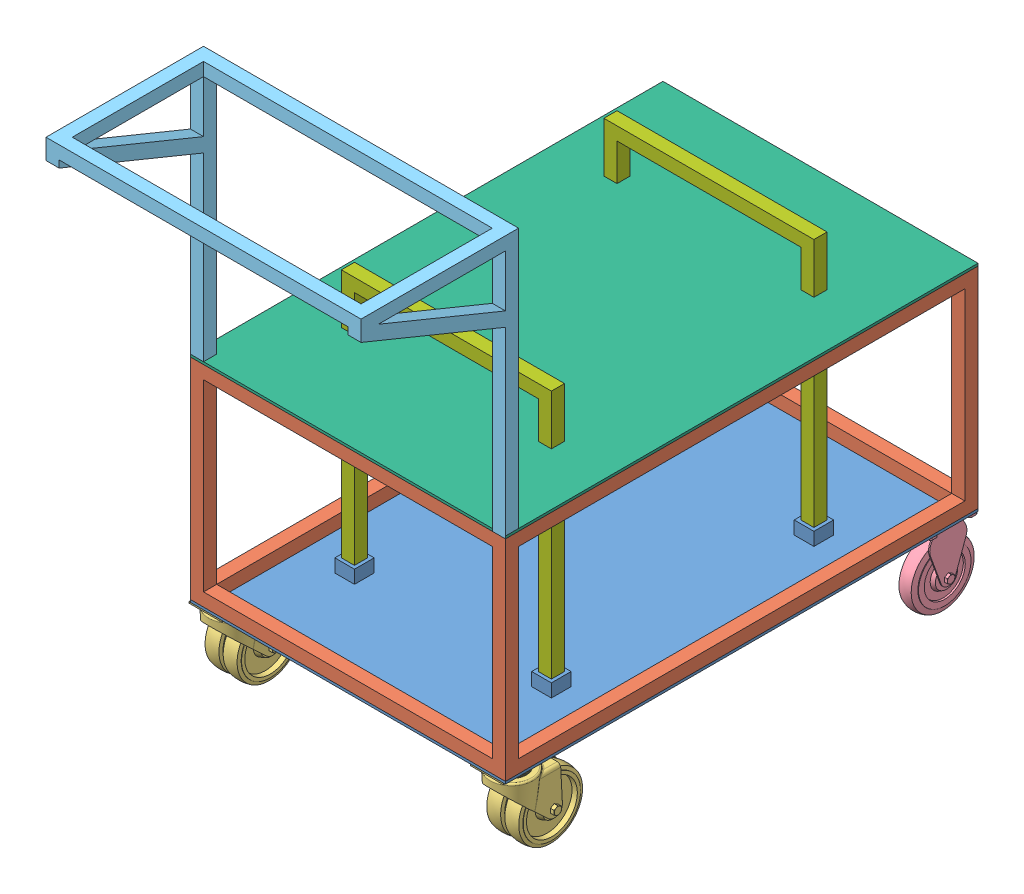
SolidWorks assembly Assem4, configuration Default. Lengths in mm.
Overall size (635.12 1076.33 1211.26).
10 component instances, 7 part files, 28 mates.
Components (placement in the parent):
- bottom plate-1: bottom plate [Default] at (-709.1986 562.6212 534.5092) size (609.6 30.16 914.4)
- frame-1: frame [Default] at (-99.5986 580.0837 534.5092) size (609.6 406.4 914.4)
- 9908T218_Cart-King Caster-1: 9908T218_Cart-King Caster [9908T218] at (-135.1319 562.6212 486.8842) x (0 0 1) z (-1 0 0) size (155.58 149.22 90.11)
- 9908T218_Cart-King Caster-2: 9908T218_Cart-King Caster [9908T218] at (-680.1501 562.6212 486.8842) x (0 0 1) z (-1 0 0) size (155.58 149.22 90.11)
- 2702T53_Cart-King Caster-1: 2702T53_Cart-King Caster [2702T53] at (-133.7299 562.6212 -333.8533) x (0 0 -1) z (1 0 0) size (127 157.16 68.26)
- 2702T53_Cart-King Caster-3: 2702T53_Cart-King Caster [2702T53] at (-675.0674 562.6212 -333.8533) x (0 0 -1) z (1 0 0) size (127 157.16 68.26)
- handle frame-1: handle frame [Default] at (-99.5986 1227.7837 509.1092) x (-1 0 0) z (0 0 -1) size (609.6 508 304.8)
- top plate-1: top plate [Default] at (-709.1986 973.7837 534.5092) size (609.6 4.76 914.4)
- legs-1: legs [Default] at (-607.5986 567.3837 -189.3908) size (406.4 508 25.4)
- legs-2: legs [Default] at (-607.5986 567.3837 318.6092) size (406.4 508 25.4)
Mates (geometry in assembly coordinates):
- Coincident5: coincident anti-aligned: plane of bottom plate-1 through (-709.1986 562.6212 534.5092) normal (0 -1 0); plane of 9908T218_Cart-King Caster-1 through (-166.8819 562.6212 439.2592) normal (0 1 0)
- Coincident6: coincident: line of bottom plate-1 through (-709.1986 562.6212 534.5092) axis (1 0 0); plane of 9908T218_Cart-King Caster-1 through (-103.3819 559.8431 534.5092) normal (0 0 1)
- Coincident10: coincident anti-aligned: plane of bottom plate-1 through (-709.1986 562.6212 534.5092) normal (0 -1 0); plane of 2702T53_Cart-King Caster-1 through (-111.0286 562.6212 -287.8158) normal (0 1 0)
- Coincident13: coincident anti-aligned: plane of bottom plate-1 through (-709.1986 562.6212 534.5092) normal (0 -1 0); plane of 2702T53_Cart-King Caster-2 through (-847.3098 567.3837 -256.8617) normal (0 1 0)
- Coincident17: coincident anti-aligned: plane of bottom plate-1 through (-709.1986 562.6212 534.5092) normal (0 -1 0); plane of 2702T53_Cart-King Caster-3 through (-652.3661 562.6212 -287.8158) normal (0 1 0)
- Coincident18: coincident aligned: line of bottom plate-1 through (-99.5986 562.6212 -379.8908) axis (-1 0 0); line of 2702T53_Cart-King Caster-3 through (-644.8985 562.6212 -379.8908) axis (-1 0 0)
- Coincident20: coincident anti-aligned: plane of bottom plate-1 through (-709.1986 562.6212 534.5092) normal (0 -1 0); plane of 9908T218_Cart-King Caster-2 through (-711.9001 562.6212 439.2592) normal (0 1 0)
- Coincident21: coincident aligned: plane of bottom plate-1 through (-709.1986 567.3837 534.5092) normal (0 0 1); plane of 9908T218_Cart-King Caster-2 through (-648.4001 559.8431 534.5092) normal (0 0 1)
- Coincident26: coincident aligned: plane of bottom plate-1 through (-709.1986 567.3837 534.5092) normal (0 0 1); plane of frame-1 through (-99.5986 592.7837 534.5092) normal (0 0 1)
- Coincident27: coincident aligned: plane of bottom plate-1 through (-709.1986 567.3837 534.5092) normal (-1 0 0); plane of frame-1 through (-709.1986 592.7837 534.5092) normal (-1 0 0)
- Coincident28: coincident anti-aligned: plane of bottom plate-1 through (-709.1986 567.3837 534.5092) normal (0 1 0); plane of frame-1 through (-99.5986 567.3837 534.5092) normal (0 -1 0)
- Coincident29: coincident anti-aligned: plane of bottom plate-1 through (-709.1986 562.6212 534.5092) normal (0 -1 0); plane of 9908T218_Cart-King Caster-2 through (-711.9001 562.6212 439.2592) normal (0 1 0)
- Coincident30: coincident anti-aligned: plane of bottom plate-1 through (-709.1986 562.6212 534.5092) normal (0 -1 0); plane of 9908T218_Cart-King Caster-1 through (-166.8819 562.6212 439.2592) normal (0 1 0)
- Parallel2: parallel aligned: plane of bottom plate-1 through (-709.1986 567.3837 534.5092) normal (0 1 0); plane of 2702T53_Cart-King Caster-3 through (-652.3661 562.6212 -287.8158) normal (0 1 0)
- Coincident34: coincident aligned: plane of bottom plate-1 through (-99.5986 567.3837 534.5092) normal (1 0 0); plane of 2702T53_Cart-King Caster-1 through (-99.5986 558.6525 -291.7782) normal (1 0 0)
- Coincident35: coincident aligned: plane of bottom plate-1 through (-709.1986 567.3837 -379.8908) normal (0 0 -1); plane of 2702T53_Cart-King Caster-1 through (-163.8987 558.6525 -379.8908) normal (0 0 -1)
- Coincident39: coincident aligned: plane of frame-1 through (-683.7986 948.3837 509.1092) normal (0 0 -1); plane of handle frame-1 through (-99.5986 1481.7837 509.1092) normal (0 0 -1)
- Coincident40: coincident anti-aligned: plane of frame-1 through (-99.5986 973.7837 534.5092) normal (0 1 0); plane of handle frame-1 through (-99.5986 973.7837 509.1092) normal (0 -1 0)
- Coincident41: coincident aligned: plane of frame-1 through (-709.1986 592.7837 534.5092) normal (-1 0 0); plane of handle frame-1 through (-709.1986 1481.7837 509.1092) normal (-1 0 0)
- Coincident42: coincident aligned: plane of frame-1 through (-709.1986 592.7837 534.5092) normal (-1 0 0); plane of top plate-1 through (-709.1986 978.5462 534.5092) normal (-1 0 0)
- Coincident43: coincident aligned: plane of frame-1 through (-99.5986 592.7837 -379.8908) normal (0 0 -1); plane of top plate-1 through (-709.1986 978.5462 -379.8908) normal (0 0 -1)
- Coincident44: coincident anti-aligned: plane of frame-1 through (-99.5986 973.7837 534.5092) normal (0 1 0); plane of top plate-1 through (-709.1986 973.7837 534.5092) normal (0 -1 0)
- Coincident45: coincident anti-aligned: plane of bottom plate-1 through (-226.5986 592.7837 -189.3908) normal (0 0 1); plane of legs-1 through (-607.5986 567.3837 -189.3908) normal (0 0 -1)
- Coincident46: coincident anti-aligned: plane of bottom plate-1 through (-607.5986 592.7837 -189.3908) normal (1 0 0); plane of legs-1 through (-607.5986 567.3837 -163.9908) normal (-1 0 0)
- Coincident47: coincident anti-aligned: plane of bottom plate-1 through (-607.5986 592.7837 344.0092) normal (1 0 0); plane of legs-2 through (-607.5986 567.3837 344.0092) normal (-1 0 0)
- Coincident48: coincident anti-aligned: plane of bottom plate-1 through (-226.5986 592.7837 318.6092) normal (0 0 1); plane of legs-2 through (-607.5986 567.3837 318.6092) normal (0 0 -1)
- Coincident49: coincident aligned: plane of legs-1 through (-607.5986 1075.3837 -163.9908) normal (0 1 0); plane of legs-2 through (-607.5986 1075.3837 344.0092) normal (0 1 0)
- Coincident50: coincident anti-aligned: plane of bottom plate-1 through (-709.1986 567.3837 534.5092) normal (0 1 0); plane of legs-2 through (-607.5986 567.3837 344.0092) normal (0 -1 0)
